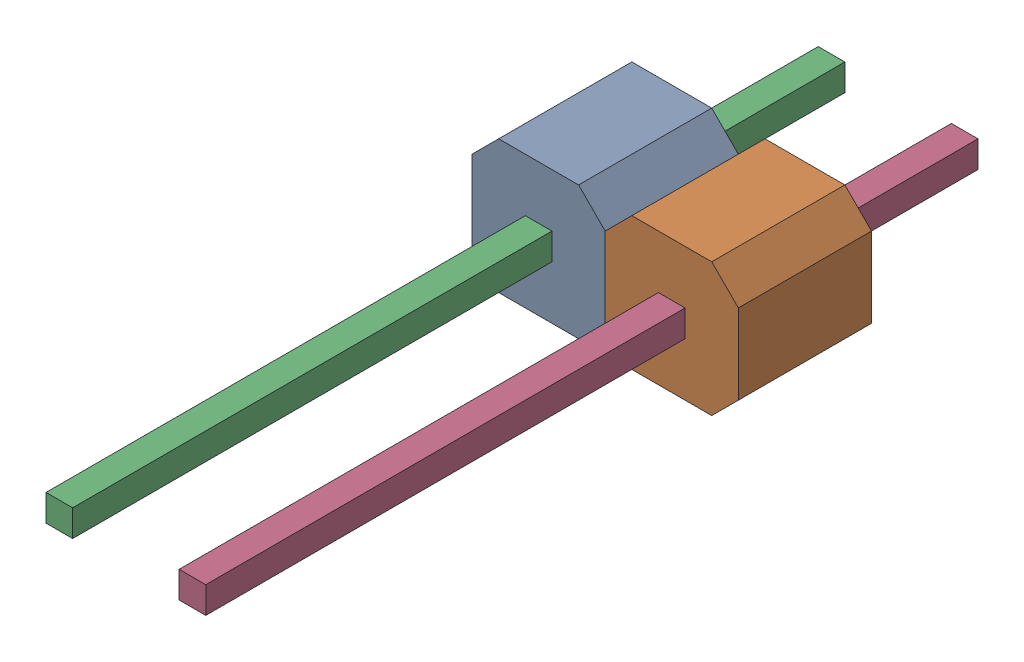
SolidWorks assembly ResetHead, configuration Default. Lengths in mm.
Overall size (5.08 2.54 14.73).
8 component instances, 2 part files, 0 mates.
Components (placement in the parent):
- 402661392-1: 402661392 [Default] at (177.7492 4.4958 0) size (2.54 2.54 2.54)
  - Extruded_20-1: Extruded_20 [Default] at origin size (2.54 2.54 2.54)
- 402661392-2: 402661392 [Default] at (180.2892 4.4958 0) size (2.54 2.54 2.54)
  - Extruded_20-1: Extruded_20 [Default] at origin size (2.54 2.54 2.54)
- 461843536-1: 461843536 [Default] at (177.7492 4.4958 -3.048) size (0.51 0.51 14.73)
  - Extruded_21-1: Extruded_21 [Default] at origin size (0.51 0.51 14.73)
- 461843536-2: 461843536 [Default] at (180.2892 4.4958 -3.048) size (0.51 0.51 14.73)
  - Extruded_21-1: Extruded_21 [Default] at origin size (0.51 0.51 14.73)
